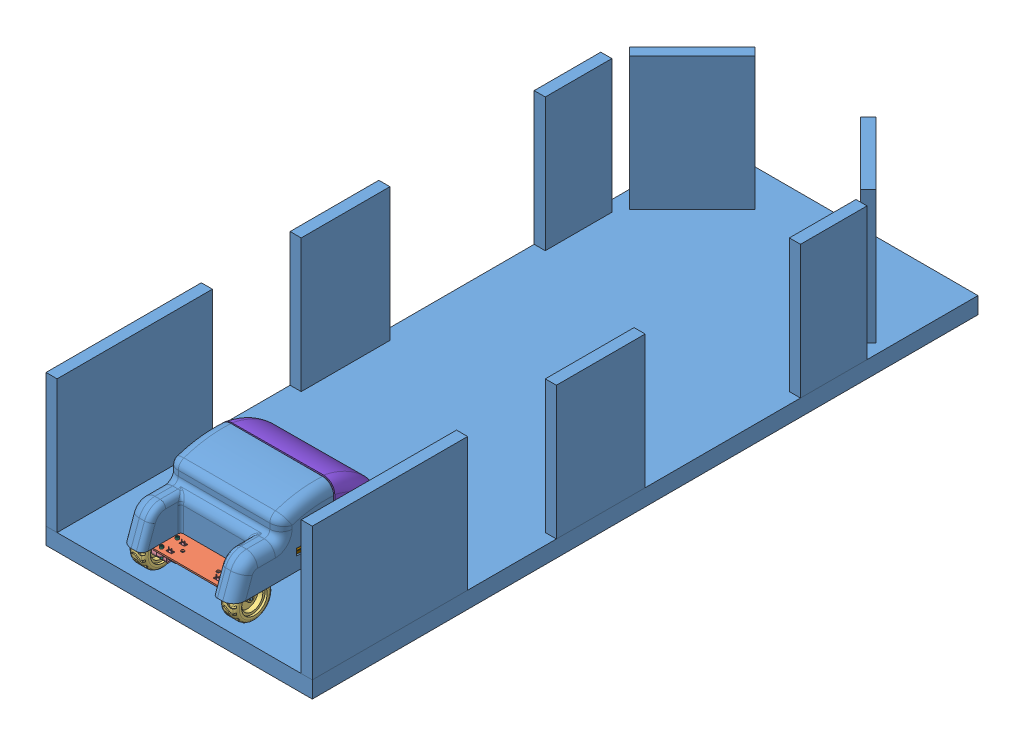
SolidWorks assembly IR Test, configuration Default. Lengths in mm.
Overall size (304.8 171.45 764.59).
95 component instances, 27 part files, 2 mates.
Components (placement in the parent):
- IR Test Course-1: IR Test Course [Default] at (-201.0081 -33.3512 70.4872) size (304.8 171.45 762)
- Full Assembly-1: Full Assembly [Default] at (-194.8096 22.9945 381.4348) size (132.16 97.66 173.6)
  - Scout Rear End-1: Scout Rear End [Default-_flexible1] at (35.9328 -37.7856 6.7097) size (131.82 96.92 114.89) (flexible)
    - Rear Baseplate-1: Rear Baseplate [Default] at (-42.1312 28.0774 12.7174) size (120.65 1.65 101.6)
    - Pololu Wheel Assembly-1: Pololu Wheel Assembly [Default-_flexible1] at (7.6153 33.3292 58.7651) x (0 0 1) z (1 0 0) size (42.46 78.6 70.03) (flexible)
      - Pololu 49x19 Wheel-1: Pololu 49x19 Wheel [Default] at (-19.8703 11.8393 2.4418) size (42.46 42.56 19)
      - Pololu Extended Micro Metal Bracket-1: Pololu Extended Micro Metal Bracket [Default] at (-19.8703 6.8393 -18.4366) size (26.6 18.17 26.04)
      - Pololu 298-1 Motor-1: Pololu 298-1 Motor [Default] at (-19.8703 11.8393 -25.1366) x (0 0 -1) z (0 1 0) size (35.87 12 10)
    - Pololu Wheel Assembly-2: Pololu Wheel Assembly [Default-_flexible2] at (-91.8778 33.3292 19.0244) x (0 0 -1) z (-1 0 0) size (42.46 78.6 70.03) (flexible)
      - Pololu 49x19 Wheel-1: Pololu 49x19 Wheel [Default] at (-19.8703 11.8393 2.4418) size (42.46 42.56 19)
      - Pololu Extended Micro Metal Bracket-1: Pololu Extended Micro Metal Bracket [Default] at (-19.8703 6.8393 -18.4366) size (26.6 18.17 26.04)
      - Pololu 298-1 Motor-1: Pololu 298-1 Motor [Default] at (-19.8703 11.8393 -25.1366) x (0 0 -1) z (0 1 0) size (35.87 12 10)
    - Socket Head Cap Screw_AI-1: Socket Head Cap Screw_AI [HX-SHCS 0.086-56x0.4375x0.4375-N] at (-77.6912 31.9128 47.8948) x (0 -1 0) z (-0.381305 0 -0.924449) size (13.3 3.56 3.56)
    - Socket Head Cap Screw_AI-2: Socket Head Cap Screw_AI [HX-SHCS 0.086-56x0.4375x0.4375-N] at (-77.6912 31.9128 29.8948) x (0 -1 0) z (0 0 1) size (13.3 3.56 3.56)
    - Socket Head Cap Screw_AI-3: Socket Head Cap Screw_AI [HX-SHCS 0.086-56x0.4375x0.4375-N] at (-6.5712 31.9128 29.8948) x (0 -1 0) z (0 0 1) size (13.3 3.56 3.56)
    - Socket Head Cap Screw_AI-4: Socket Head Cap Screw_AI [HX-SHCS 0.086-56x0.4375x0.4375-N] at (-6.5712 31.9128 47.8948) x (0 -1 0) z (0 0 1) size (13.3 3.56 3.56)
    - Mounting Block-1: Mounting Block [Default] at (-42.1312 34.8084 -38.8462) x (-1 0 0) z (0 0 -1) size (22.23 10.17 19.05)
    - Side IR Mount-3: Side IR Mount [Default] at (-88.5751 48.7784 -43.2912) size (6.35 38.1 46.99)
    - Side IR Mount-4: Side IR Mount [Default] at (4.3127 48.7784 3.6988) x (-1 0 0) z (0 0 -1) size (6.35 38.1 46.99)
    - gp2d12-4: gp2d12 [Default] at (5.0747 48.7784 -19.7962) x (0 0 1) z (1 0 0) size (44.5 18.9 13.5)
    - 4000mAh 7.4V Battery Pack-1: 4000mAh 7.4V Battery Pack [Default] at (-42.1312 46.8734 -10.9062) x (0 0 -1) z (1 0 0) size (34.29 34.29 63.5)
    - mmc90136A465-1: mmc90136A465 [Default] at (7.0747 48.7784 -1.2962) x (0 -1 0) z (0 0 1) size (6.62 6.16 6.63)
    - mmc90136A465-2: mmc90136A465 [Default] at (7.0747 48.7784 -38.2962) x (0 -1 0) z (0 0 1) size (6.62 6.16 6.63)
    - mmc90136A465-3: mmc90136A465 [Default] at (-91.3371 48.7784 -38.2962) x (0 -0.381849 0.924225) z (0 -0.924225 -0.381849) size (6.62 6.16 6.63)
    - mmc90136A465-4: mmc90136A465 [Default] at (-91.3371 48.7784 -1.2962) x (0 -0.381849 0.924225) z (0 -0.924225 -0.381849) size (6.62 6.16 6.63)
    - Socket Button Head Cap Screw_AI-1: Socket Button Head Cap Screw_AI [SBHCSCREW 0.086-56x0.125-HX-N] at (8.6688 26.909 -38.8462) x (0 1 0) z (0 0 1) size (4.34 4.17 4.17)
    - Socket Button Head Cap Screw_AI-2: Socket Button Head Cap Screw_AI [SBHCSCREW 0.086-56x0.125-HX-N] at (-92.9312 26.909 -38.8462) x (0 1 0) z (0 0 1) size (4.34 4.17 4.17)
    - Socket Button Head Cap Screw_AI-3: Socket Button Head Cap Screw_AI [SBHCSCREW 0.086-56x0.125-HX-N] at (-92.9312 26.909 -0.7462) x (0 1 0) z (0 0 1) size (4.34 4.17 4.17)
    - Socket Button Head Cap Screw_AI-4: Socket Button Head Cap Screw_AI [SBHCSCREW 0.086-56x0.125-HX-N] at (8.6688 26.909 -0.7462) x (0 1 0) z (0 0 1) size (4.34 4.17 4.17)
    - Socket Countersunk Head Cap Screw_AI2-1: Socket Countersunk Head Cap Screw_AI2 [SCHCSCREW 0.112-40x0.25x0.25-HX-N] at (-50.3862 28.0619 -44.5612) x (0 1 0) z (-0.806365 0 0.591418) size (6.35 6.29 6.29)
    - Socket Countersunk Head Cap Screw_AI2-2: Socket Countersunk Head Cap Screw_AI2 [SCHCSCREW 0.112-40x0.25x0.25-HX-N] at (-50.3862 28.0619 -33.1312) x (0 1 0) z (0 0 1) size (6.35 6.29 6.29)
    - Socket Countersunk Head Cap Screw_AI2-3: Socket Countersunk Head Cap Screw_AI2 [SCHCSCREW 0.112-40x0.25x0.25-HX-N] at (-33.8762 28.0619 -33.1312) x (0 1 0) z (0 0 1) size (6.35 6.29 6.29)
    - Socket Countersunk Head Cap Screw_AI2-4: Socket Countersunk Head Cap Screw_AI2 [SCHCSCREW 0.112-40x0.25x0.25-HX-N] at (-33.8762 28.0619 -44.5612) x (0 1 0) z (0 0 1) size (6.35 6.29 6.29)
    - Main PCB-1: Main PCB [Default] at (-42.357 67.8284 -19.0109) size (120.65 6.68 50.8)
    - XBEE Pro-1: XBEE Pro [Défaut] at (3.3895 71.9686 -30.0445) x (1 0 0) z (0 1 0) size (24.38 32.94 13.59)
      - XBEE PCB-1: XBEE PCB [Défaut] at origin size (24.38 32.94 0.8)
      - MTMM-106-09-X-S-350-1: MTMM-106-09-X-S-350 [Défaut] at (-9.8374 3.8829 -0.8763) x (0 1 0) z (-1 0 0) size (20 13.59 1.98)
      - MTMM-106-09-X-S-350-2: MTMM-106-09-X-S-350 [Défaut] at (12.1626 3.8829 -0.8763) x (0 1 0) z (-1 0 0) size (20 13.59 1.98)
    - Rear Battery Strap-2: Rear Battery Strap [Default] at (-42.1312 52.7662 -28.0512) size (92.89 12.7 6.35)
    - Socket Button Head Cap Screw_AI-5: Socket Button Head Cap Screw_AI [SBHCSCREW 0.086-56x0.125-HX-N] at (-86.6447 59.1162 -31.2262) x (-1 0 0) z (0 0 1) size (4.34 4.17 4.17)
    - Socket Button Head Cap Screw_AI-6: Socket Button Head Cap Screw_AI [SBHCSCREW 0.086-56x0.125-HX-N] at (2.3823 59.1162 -31.2262) x (1 0 0) z (0 -0.924225 -0.381849) size (4.34 4.17 4.17)
    - GP2Y0D810 Sensor-1: GP2Y0D810 Sensor [Default] at (-94.9417 37.9643 -19.7962) x (0 0 1) z (-0.766044 0.642788 0) size (22.86 11.11 8.89)
    - gp2d12-5: gp2d12 [Default] at (-89.3371 48.7784 -19.7962) x (0 0 -1) z (-1 0 0) size (44.5 18.9 13.5)
    - GP2Y0D810 Sensor-2: GP2Y0D810 Sensor [Default] at (10.6792 37.9643 -19.7962) x (0 0 1) z (-0.766044 -0.642788 0) size (22.86 11.11 8.89)
    - Rear Shell-1: Rear Shell [Default] at (-42.1312 29.7284 65.9288) x (0 0 -1) z (1 0 0) size (114.3 67.39 131.82)
  - Scout Front End-1: Scout Front End [Default] at (70.5492 -55.8048 -62.0375) x (0.999986 0.005361 0) z (0 0 1) size (131.64 96.95 57.9)
    - Front Baseplate-1: Front Baseplate [Default] at (-76.4634 46.5072 -32.0242) size (120.65 1.65 50.8)
    - Pololu Wheel Assembly-1: Pololu Wheel Assembly [Default-_flexible3] at (-26.7168 51.7591 2.1802) x (0 0 1) z (1 0 0) size (42.46 78.6 70.03) (flexible)
      - Pololu 49x19 Wheel-1: Pololu 49x19 Wheel [Default] at (-19.8703 11.8393 2.4418) size (42.46 42.56 19)
      - Pololu Extended Micro Metal Bracket-1: Pololu Extended Micro Metal Bracket [Default] at (-19.8703 6.8393 -18.4366) size (26.6 18.17 26.04)
      - Pololu 298-1 Motor-1: Pololu 298-1 Motor [Default] at (-19.8703 11.8393 -25.1366) x (0 0 -1) z (0 1 0) size (35.87 12 10)
    - Pololu Wheel Assembly-2: Pololu Wheel Assembly [Default-_flexible4] at (-126.21 51.7591 -37.5605) x (0 0 -1) z (-1 0 0) size (42.46 78.6 70.03) (flexible)
      - Pololu 49x19 Wheel-1: Pololu 49x19 Wheel [Default] at (-19.8703 11.8393 2.4418) size (42.46 42.56 19)
      - Pololu Extended Micro Metal Bracket-1: Pololu Extended Micro Metal Bracket [Default] at (-19.8703 6.8393 -18.4366) size (26.6 18.17 26.04)
      - Pololu 298-1 Motor-1: Pololu 298-1 Motor [Default] at (-19.8703 11.8393 -25.1366) x (0 0 -1) z (0 1 0) size (35.87 12 10)
    - Socket Head Cap Screw_AI-1: Socket Head Cap Screw_AI [HX-SHCS 0.086-56x0.4375x0.4375-N] at (-112.0234 50.3426 -8.6902) x (0 -1 0) z (0.989468 0 0.144748) size (13.3 3.56 3.56)
    - Socket Head Cap Screw_AI-2: Socket Head Cap Screw_AI [HX-SHCS 0.086-56x0.4375x0.4375-N] at (-40.9034 50.3426 -26.6902) x (0 -1 0) z (0.390166 0 -0.920744) size (13.3 3.56 3.56)
    - Socket Head Cap Screw_AI-3: Socket Head Cap Screw_AI [HX-SHCS 0.086-56x0.4375x0.4375-N] at (-40.9034 50.3426 -8.6902) x (0 -1 0) z (0.700957 0 0.713204) size (13.3 3.56 3.56)
    - Socket Head Cap Screw_AI-4: Socket Head Cap Screw_AI [HX-SHCS 0.086-56x0.4375x0.4375-N] at (-112.0234 50.3426 -26.6902) x (0 -1 0) z (-0.920661 0 -0.390363) size (13.3 3.56 3.56)
    - Mounting Block-1: Mounting Block [Default] at (-76.4634 53.2382 9.2508) size (22.23 10.17 19.05)
    - gp2d12-2: gp2d12 [Default] at (-76.4634 67.9702 -19.3242) x (1 0 0) z (0 0 -1) size (44.5 18.9 13.5)
    - gp2d12-3: gp2d12 [Default] at (-36.6376 67.9702 -2.9934) x (0.707107 0 0.707107) z (0.707107 0 -0.707107) size (44.5 18.9 13.5)
    - gp2d12-4: gp2d12 [Default] at (-116.2892 67.9702 -2.9934) x (0.707107 0 -0.707107) z (-0.707107 0 -0.707107) size (44.5 18.9 13.5)
    - Front IR Mount-1: Front IR Mount [Default] at (-76.4634 61.6202 -19.3242) size (110.93 28.52 37)
    - Bumper-2: Bumper [Default] at (-76.4634 36.9822 -26.9442) x (-1 0 0) z (0 0 -1) size (50.8 9.53 6.35)
    - mmc90136A465-1: mmc90136A465 [Default] at (-104.6219 67.9702 -17.4891) x (0.5 0.707107 -0.5) z (-0.5 0.707107 0.5) size (6.62 6.16 6.63)
    - mmc90136A465-2: mmc90136A465 [Default] at (-130.7849 67.9702 8.6739) x (0.5 0.707107 -0.5) z (-0.5 0.707107 0.5) size (6.62 6.16 6.63)
    - mmc90136A465-3: mmc90136A465 [Default] at (-48.3049 67.9702 -17.4891) x (0.5 -0.707107 0.5) z (0.5 0.707107 0.5) size (6.62 6.16 6.63)
    - mmc90136A465-4: mmc90136A465 [Default] at (-22.1419 67.9702 8.6739) x (0.5 -0.707107 0.5) z (0.5 0.707107 0.5) size (6.62 6.16 6.63)
    - mmc90136A465-5: mmc90136A465 [Default] at (-57.9634 67.9702 -21.3242) x (1 0 0) z (0 1 0) size (6.62 6.16 6.63)
    - mmc90136A465-6: mmc90136A465 [Default] at (-94.9634 67.9702 -21.3242) x (1 0 0) z (0 1 0) size (6.62 6.16 6.63)
    - Sensor PCB-1: Sensor PCB [Default] at (-76.463 60.02 -17.973) size (110.8 1.6 35.94)
    - Sensor PCB Standoff-1: Sensor PCB Standoff [Default] at (-103.3504 48.1582 39.1442) size (7.33 17.45 6.58)
    - Sensor PCB Standoff-2: Sensor PCB Standoff [Default] at (-3.2231 48.1582 39.1442) size (7.33 17.45 6.58)
    - Socket Countersunk Head Cap Screw_AI2-1: Socket Countersunk Head Cap Screw_AI2 [SCHCSCREW 0.112-40x0.25x0.25-HX-N] at (-68.2084 46.5072 3.5358) x (0 1 0) z (0 0 1) size (6.35 6.29 6.29)
    - Socket Countersunk Head Cap Screw_AI2-2: Socket Countersunk Head Cap Screw_AI2 [SCHCSCREW 0.112-40x0.25x0.25-HX-N] at (-84.7184 46.5072 3.5358) x (0 1 0) z (0 0 1) size (6.35 6.29 6.29)
    - Socket Countersunk Head Cap Screw_AI2-3: Socket Countersunk Head Cap Screw_AI2 [SCHCSCREW 0.112-40x0.25x0.25-HX-N] at (-84.7184 46.5072 14.9658) x (0 1 0) z (0 0 1) size (6.35 6.29 6.29)
    - Socket Countersunk Head Cap Screw_AI2-4: Socket Countersunk Head Cap Screw_AI2 [SCHCSCREW 0.112-40x0.25x0.25-HX-N] at (-68.2084 46.5072 14.9658) x (0 1 0) z (0.335002 0 0.942218) size (6.35 6.29 6.29)
    - Socket Button Head Cap Screw_AI-1: Socket Button Head Cap Screw_AI [SBHCSCREW 0.086-56x0.25-HX-N] at (-126.5267 62.7886 13.7099) x (0 -1 0) z (-0.546944 0 0.837169) size (7.52 4.17 4.17)
    - Socket Button Head Cap Screw_AI-2: Socket Button Head Cap Screw_AI [SBHCSCREW 0.086-56x0.25-HX-N] at (-99.5859 62.7886 -13.2309) x (0 -1 0) z (0 0 1) size (7.52 4.17 4.17)
    - Socket Button Head Cap Screw_AI-3: Socket Button Head Cap Screw_AI [SBHCSCREW 0.086-56x0.25-HX-N] at (-53.3401 62.7886 -13.2309) x (0 -1 0) z (0 0 1) size (7.52 4.17 4.17)
    - Socket Button Head Cap Screw_AI-4: Socket Button Head Cap Screw_AI [SBHCSCREW 0.086-56x0.25-HX-N] at (-26.3994 62.7886 13.7099) x (0 -1 0) z (0.705183 0 0.709025) size (7.52 4.17 4.17)
    - Sensor PCB-2: Sensor PCB [Default] at (-76.463 76.6824 -17.973) size (110.8 1.6 35.94)
    - Socket Button Head Cap Screw_AI-6: Socket Button Head Cap Screw_AI [SBHCSCREW 0.086-56x0.188-HX-N] at (-99.5859 79.451 -13.2309) x (0 -1 0) z (0.836581 0 0.547843) size (5.94 4.17 4.17)
    - Socket Button Head Cap Screw_AI-9: Socket Button Head Cap Screw_AI [SBHCSCREW 0.086-56x0.188-HX-N] at (-53.3401 79.451 -13.2309) x (0 -1 0) z (0.836581 0 0.547843) size (5.94 4.17 4.17)
    - Socket Button Head Cap Screw_AI-10: Socket Button Head Cap Screw_AI [SBHCSCREW 0.086-56x0.188-HX-N] at (-126.5267 79.451 13.7099) x (0 -1 0) z (-0.886365 0 0.462987) size (5.94 4.17 4.17)
    - Socket Button Head Cap Screw_AI-11: Socket Button Head Cap Screw_AI [SBHCSCREW 0.086-56x0.188-HX-N] at (-26.3994 79.451 13.7099) x (0 -1 0) z (-0.895952 0 0.444151) size (5.94 4.17 4.17)
    - LED Dome-1: LED Dome [Default] at (-96.5883 78.2826 -4.7508) size (12.7 12.7 12.7)
    - LED Dome-2: LED Dome [Default] at (-55.903 78.2826 -4.7508) size (12.7 12.7 12.7)
    - gp2d12-5: gp2d12 [Default] at (-76.4634 54.6582 -4.5542) x (1 0 0) z (0 0 -1) size (44.5 18.9 13.5)
    - GP2Y0D810 Sensor-1: GP2Y0D810 Sensor [Default] at (-76.4634 48.1582 -24.8487) size (22.86 11.11 8.89)
    - Socket Head Cap Screw_AI-5: Socket Head Cap Screw_AI [HX-SHCS 0.086-56x0.188x0.188-N] at (-61.2234 50.3426 -29.9922) x (0 -1 0) z (-0.920661 0 -0.390363) size (6.96 3.56 3.56)
    - Socket Head Cap Screw_AI-6: Socket Head Cap Screw_AI [HX-SHCS 0.086-56x0.188x0.188-N] at (-91.7034 50.3426 -29.9922) x (0 -1 0) z (-0.920661 0 -0.390363) size (6.96 3.56 3.56)
    - Front Shell-1: Front Shell [Default] at (-76.4634 48.1582 133.0758) x (0 0 -1) z (1 0 0) size (50.8 67.64 131.64)
  - 6655k13 Thrust Washers-1: 6655k13 Thrust Washers [Default] at (-6.1984 -2.9772 -42.4616) x (0 0 -1) z (1 0 0) size (4.9 14.15 14.15)
Mates (geometry in assembly coordinates):
- Distance1: distance = 21 mm anti-aligned: plane of Full Assembly-1/Scout Rear End-1/Pololu Wheel Assembly-1/Pololu 49x19 Wheel-1 through (-148.8197 6.6988 427.0394) normal (0 -1 0); plane of IR Test Course-1 through (-48.6081 -14.3012 -310.5128) normal (0 1 0)
- Coincident2: coincident aligned: plane of Full Assembly-1/Scout Rear End-1/Rear Baseplate-1 through (-201.0081 13.2863 400.862) normal (1 0 0); plane of IR Test Course-1 through (-201.0081 -33.3512 70.4872) normal (1 0 0)
